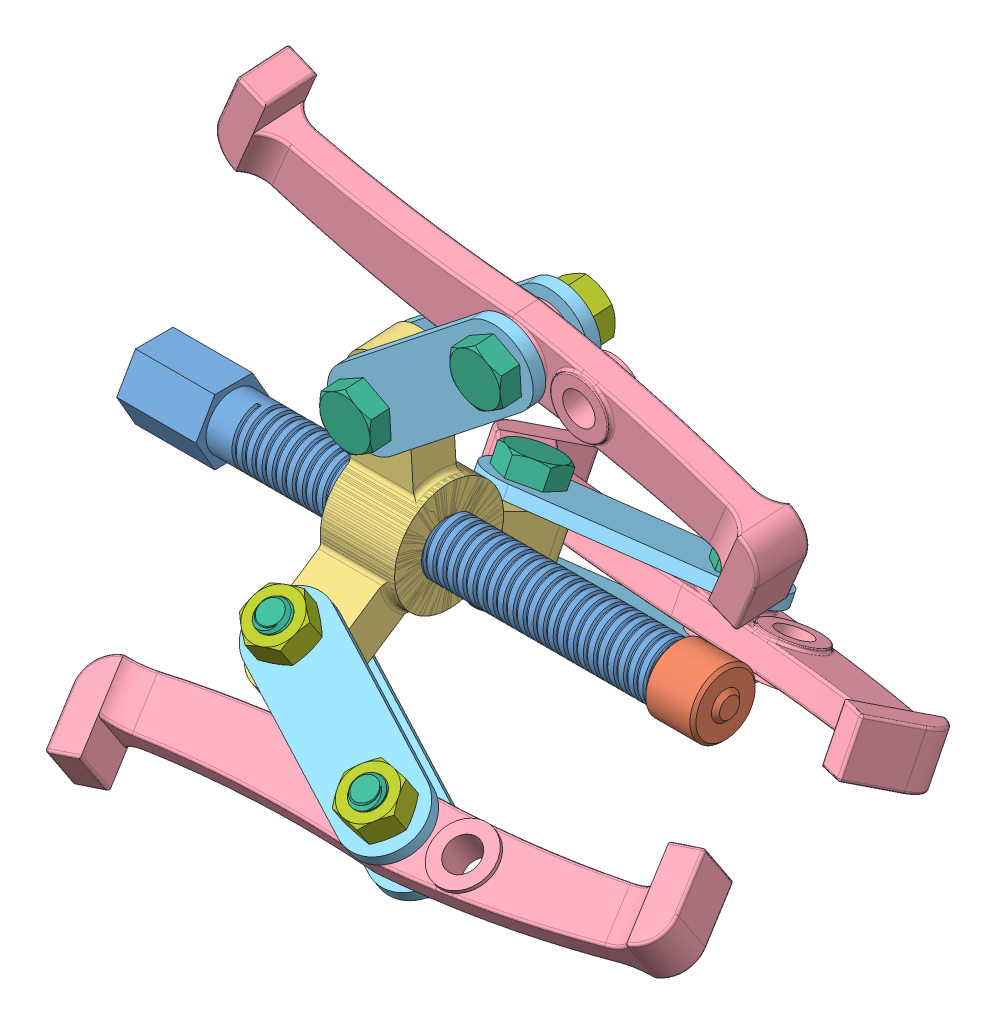
SolidWorks assembly DRAFT41-63 ASSEMBLY, configuration Default. Lengths in mm.
Overall size (173.92 155.65 156.59).
24 component instances, 7 part files, 48 mates.
Components (placement in the parent):
- DRAFT41-63 PUSH SCREW-1: DRAFT41-63 PUSH SCREW [Default] at origin size (144.02 16.5 19.05)
- DRAFT41-63E PUSH SCREW END-1: DRAFT41-63E PUSH SCREW END [Default] at (12.7 0 0) x (1 0 0) z (0 -0.815917 0.578169) size (13.72 16.51 16.51)
- DRAFT41-63 Y JOINT-1: DRAFT41-63 Y JOINT [Default] at (-76.0434 0 0) x (0 0.061257 -0.998122) z (0 -0.998122 -0.061257) size (76.61 18.8 66.34)
- DRAFT41-63A PULLER ARM-1: DRAFT41-63A PULLER ARM [Default] at (-37.0809 58.5168 3.5913) x (0.412849 0.909089 0.055793) z (0 -0.061257 0.998122) size (37.12 137.16 14.1)
- DRAFT41-63A LINKAGE-1: DRAFT41-63A LINKAGE [Default] at (-33.3881 57.3763 12.1354) x (0.779625 0.625071 0.038362) z (0 -0.061257 0.998122) size (63.5 19.05 3.17)
- DRAFT41-63A LINKAGE-2: DRAFT41-63A LINKAGE [Default] at (-33.3881 58.2351 -1.8591) x (0.779625 0.625071 0.038362) z (0 -0.061257 0.998122) size (63.5 19.05 3.17)
- 92240A583_18-8 Stainless Steel Hex Head Screw-1: 92240A583_18-8 Stainless Steel Hex Head Screw [92240A583] at (-68.0424 29.5918 10.4302) x (1 0 0) z (0 -0.061257 0.998122) size (12.7 14.66 31.1)
- 95505A602_Medium-Strength Steel Hex Nut-1: 95505A602_Medium-Strength Steel Hex Nut [95505A602] at (-68.0424 30.8519 -10.1004) x (0.994196 -0.107382 -0.00659) z (0 -0.061257 0.998122) size (12.7 14.66 7.85)
- 92240A583_18-8 Stainless Steel Hex Head Screw-2: 92240A583_18-8 Stainless Steel Hex Head Screw [92240A583] at (-33.3881 57.3763 12.1354) x (1 0 0) z (0 -0.061257 0.998122) size (12.7 14.66 31.1)
- 95505A602_Medium-Strength Steel Hex Nut-2: 95505A602_Medium-Strength Steel Hex Nut [95505A602] at (-33.3881 58.6363 -8.3952) x (1 0 0) z (0 0.061257 -0.998122) size (12.7 14.66 7.85)
- DRAFT41-63A LINKAGE-3: DRAFT41-63A LINKAGE [Default] at (-28.0194 -20.1681 46.0296) x (0.900406 -0.240197 0.362733) z (0 0.83377 0.552111) size (63.5 19.05 3.17)
- DRAFT41-63A LINKAGE-4: DRAFT41-63A LINKAGE [Default] at (-28.0194 -31.8583 38.2886) x (0.900406 -0.240197 0.362733) z (0 0.83377 0.552111) size (63.5 19.05 3.17)
- DRAFT41-63A PULLER ARM-2: DRAFT41-63A PULLER ARM [Default] at (-31.7616 -27.3954 41.3711) x (0.284892 -0.529232 0.799219) z (0 -0.83377 -0.552111) size (37.12 137.16 14.1)
- 92240A583_18-8 Stainless Steel Hex Head Screw-3: 92240A583_18-8 Stainless Steel Hex Head Screw [92240A583] at (-68.0424 -23.8287 20.4122) x (-0.503529 -0.477012 0.72036) z (0 -0.83377 -0.552111) size (12.7 14.66 31.1)
- 95505A602_Medium-Strength Steel Hex Nut-3: 95505A602_Medium-Strength Steel Hex Nut [95505A602] at (-68.0424 -6.6787 31.7687) x (-0.317356 0.523571 -0.79067) z (0 0.83377 0.552111) size (12.7 14.66 7.85)
- 92240A583_18-8 Stainless Steel Hex Head Screw-4: 92240A583_18-8 Stainless Steel Hex Head Screw [92240A583] at (-28.0194 -34.5055 36.5357) x (0.593838 -0.44422 0.670839) z (0 -0.83377 -0.552111) size (12.7 14.66 31.1)
- 95505A602_Medium-Strength Steel Hex Nut-4: 95505A602_Medium-Strength Steel Hex Nut [95505A602] at (-28.0194 -17.3555 47.8922) x (0.932993 0.198703 -0.30007) z (0 -0.83377 -0.552111) size (12.7 14.66 7.85)
- DRAFT41-63A PULLER ARM-3: DRAFT41-63A PULLER ARM [Default] at (-29.676 -20.0922 -40.3199) x (0.391979 -0.410318 -0.823402) z (0 0.895028 -0.446011) size (37.12 137.16 14.1)
- DRAFT41-63A LINKAGE-5: DRAFT41-63A LINKAGE [Default] at (-25.97 -27.5509 -36.0102) x (0.94651 -0.143917 -0.288804) z (0 -0.895028 0.446011) size (63.5 19.05 3.17)
- DRAFT41-63A LINKAGE-6: DRAFT41-63A LINKAGE [Default] at (-25.97 -15.0019 -42.2636) x (0.94651 -0.143917 -0.288804) z (0 -0.895028 0.446011) size (63.5 19.05 3.17)
- 92240A583_18-8 Stainless Steel Hex Head Screw-5: 92240A583_18-8 Stainless Steel Hex Head Screw [92240A583] at (-68.0424 -5.7631 -30.8424) x (0.553703 0.371399 0.745303) z (0 0.895028 -0.446011) size (12.7 14.66 31.1)
- 95505A602_Medium-Strength Steel Hex Nut-5: 95505A602_Medium-Strength Steel Hex Nut [95505A602] at (-68.0424 -24.1731 -21.6683) x (1 0 0) z (0 -0.895028 0.446011) size (12.7 14.66 7.85)
- 92240A583_18-8 Stainless Steel Hex Head Screw-6: 92240A583_18-8 Stainless Steel Hex Head Screw [92240A583] at (-25.97 -12.1602 -43.6797) x (0.63314 -0.345229 -0.692785) z (0 0.895028 -0.446011) size (12.7 14.66 31.1)
- 95505A602_Medium-Strength Steel Hex Nut-6: 95505A602_Medium-Strength Steel Hex Nut [95505A602] at (-25.97 -30.5702 -34.5056) x (0.991794 0.05702 0.114423) z (0 -0.895028 0.446011) size (12.7 14.66 7.85)
Mates (geometry in assembly coordinates):
- Concentric1: concentric anti-aligned: circle of DRAFT41-63 PUSH SCREW-1; circle of DRAFT41-63E PUSH SCREW END-1
- Coincident2: coincident anti-aligned: plane of DRAFT41-63 PUSH SCREW-1 through (10.16 0 0) normal (1 0 0); plane of DRAFT41-63E PUSH SCREW END-1 through (10.16 0 0) normal (-1 0 0)
- Concentric2: concentric aligned: circle of DRAFT41-63 PUSH SCREW-1; circle of DRAFT41-63 Y JOINT-1
- Concentric4: concentric anti-aligned: cylinder of DRAFT41-63 Y JOINT-1 through (-68.0424 27.7722 40.0792) axis (0 0.061257 -0.998122) radius 4.0323; cylinder of DRAFT41-63A LINKAGE-1 through (-68.0424 29.7863 7.2612) axis (0 -0.061257 0.998122) radius 4.7625
- Coincident3: coincident anti-aligned: plane of DRAFT41-63 Y JOINT-1 through (-60.0414 -14.0995 4.5678) normal (0 -0.061257 0.998122); plane of DRAFT41-63A LINKAGE-1 through (-33.3881 57.5707 8.9664) normal (0 0.061257 -0.998122)
- Concentric5: concentric anti-aligned: cylinder of DRAFT41-63 Y JOINT-1 through (-68.0424 27.7722 40.0792) axis (0 0.061257 -0.998122) radius 4.0323; cylinder of DRAFT41-63A LINKAGE-2 through (-68.0424 30.6452 -6.7333) axis (0 -0.061257 0.998122) radius 4.7625
- Coincident4: coincident anti-aligned: plane of DRAFT41-63 Y JOINT-1 through (-68.0424 33.3662 -3.3853) normal (0 0.061257 -0.998122); plane of DRAFT41-63A LINKAGE-2 through (-33.3881 58.2351 -1.8591) normal (0 -0.061257 0.998122)
- Concentric7: concentric aligned: cylinder of DRAFT41-63A LINKAGE-1 through (-33.3881 57.5707 8.9664) axis (0 -0.061257 0.998122) radius 4.7625; cylinder of DRAFT41-63A LINKAGE-2 through (-33.3881 58.4296 -5.0281) axis (0 -0.061257 0.998122) radius 4.7625
- Concentric8: concentric anti-aligned: cylinder of DRAFT41-63A PULLER ARM-1 through (-33.3881 57.6275 8.041) axis (0 0.061257 -0.998122) radius 4.1021; cylinder of DRAFT41-63A LINKAGE-1 through (-33.3881 57.5707 8.9664) axis (0 -0.061257 0.998122) radius 4.7625
- Width1: width anti-aligned: plane of DRAFT41-63A LINKAGE-2 through (-33.3881 58.2351 -1.8591) normal (0 -0.061257 0.998122); plane of DRAFT41-63A LINKAGE-1 through (-33.3881 57.5707 8.9664) normal (0 0.061257 -0.998122); plane of DRAFT41-63A PULLER ARM-1 through (-33.3881 58.1783 -0.9337) normal (0 0.061257 -0.998122); plane of DRAFT41-63A PULLER ARM-1 through (-33.3881 57.6275 8.041) normal (0 -0.061257 0.998122)
- Concentric9: concentric aligned: cylinder of DRAFT41-63 Y JOINT-1 through (-68.0424 27.7722 40.0792) axis (0 0.061257 -0.998122) radius 4.0323; circle of 92240A583_18-8 Stainless Steel Hex Head Screw-1
- Coincident5: coincident anti-aligned: plane of DRAFT41-63A LINKAGE-1 through (-33.3881 57.3763 12.1354) normal (0 -0.061257 0.998122); plane of 92240A583_18-8 Stainless Steel Hex Head Screw-1 through (-61.6924 33.2511 10.6548) normal (0 0.061257 -0.998122)
- Concentric10: concentric aligned: circle of DRAFT41-63A LINKAGE-2; circle of 95505A602_Medium-Strength Steel Hex Nut-1
- Coincident6: coincident anti-aligned: plane of DRAFT41-63A LINKAGE-2 through (-33.3881 58.4296 -5.0281) normal (0 0.061257 -0.998122); plane of 95505A602_Medium-Strength Steel Hex Nut-1 through (-73.9611 34.9651 -6.4682) normal (0 -0.061257 0.998122)
- Concentric11: concentric anti-aligned: circle of DRAFT41-63A LINKAGE-1; circle of 92240A583_18-8 Stainless Steel Hex Head Screw-2
- Coincident7: coincident anti-aligned: plane of DRAFT41-63A LINKAGE-1 through (-33.3881 57.3763 12.1354) normal (0 -0.061257 0.998122); plane of 92240A583_18-8 Stainless Steel Hex Head Screw-2 through (-27.0381 61.0355 12.36) normal (0 0.061257 -0.998122)
- Concentric12: concentric aligned: circle of 92240A583_18-8 Stainless Steel Hex Head Screw-2; circle of 95505A602_Medium-Strength Steel Hex Nut-2
- Coincident8: coincident anti-aligned: plane of DRAFT41-63A LINKAGE-2 through (-33.3881 58.4296 -5.0281) normal (0 0.061257 -0.998122); plane of 95505A602_Medium-Strength Steel Hex Nut-2 through (-39.7381 54.7703 -5.2527) normal (0 -0.061257 0.998122)
- Concentric13: concentric anti-aligned: cylinder of DRAFT41-63 Y JOINT-1 through (-68.0424 28.9826 55.3832) axis (0 -0.83377 -0.552111) radius 4.0323; cylinder of DRAFT41-63A LINKAGE-3 through (-68.0424 -12.1386 28.1532) axis (0 0.83377 0.552111) radius 4.7625
- Coincident9: coincident anti-aligned: plane of DRAFT41-63 Y JOINT-1 through (-68.0424 -13.7513 30.5887) normal (0 0.83377 0.552111); plane of DRAFT41-63A LINKAGE-3 through (-28.0194 -22.8154 44.2767) normal (0 -0.83377 -0.552111)
- Concentric14: concentric anti-aligned: cylinder of DRAFT41-63 Y JOINT-1 through (-68.0424 28.9826 55.3832) axis (0 -0.83377 -0.552111) radius 4.0323; cylinder of DRAFT41-63A LINKAGE-4 through (-68.0424 -23.8287 20.4122) axis (0 0.83377 0.552111) radius 4.7625
- Coincident10: coincident anti-aligned: plane of DRAFT41-63 Y JOINT-1 through (-60.0414 3.0939 -14.4944) normal (0 -0.83377 -0.552111); plane of DRAFT41-63A LINKAGE-4 through (-28.0194 -31.8583 38.2886) normal (0 0.83377 0.552111)
- Concentric15: concentric aligned: cylinder of DRAFT41-63A LINKAGE-3 through (-28.0194 -22.8154 44.2767) axis (0 0.83377 0.552111) radius 4.7625; cylinder of DRAFT41-63A LINKAGE-4 through (-28.0194 -34.5055 36.5357) axis (0 0.83377 0.552111) radius 4.7625
- Concentric16: concentric aligned: cylinder of DRAFT41-63A LINKAGE-3 through (-28.0194 -22.8154 44.2767) axis (0 0.83377 0.552111) radius 4.7625; cylinder of DRAFT41-63A PULLER ARM-2 through (-28.0194 -31.0853 38.8005) axis (0 0.83377 0.552111) radius 4.1021
- Width2: width aligned: plane of DRAFT41-63A LINKAGE-4 through (-28.0194 -31.8583 38.2886) normal (0 0.83377 0.552111); plane of DRAFT41-63A LINKAGE-3 through (-28.0194 -22.8154 44.2767) normal (0 -0.83377 -0.552111); plane of DRAFT41-63A PULLER ARM-2 through (-28.0194 -23.5883 43.7648) normal (0 0.83377 0.552111); plane of DRAFT41-63A PULLER ARM-2 through (-28.0194 -31.0853 38.8005) normal (0 -0.83377 -0.552111)
- Concentric17: concentric aligned: circle of DRAFT41-63A LINKAGE-3; circle of 95505A602_Medium-Strength Steel Hex Nut-3
- Coincident11: coincident anti-aligned: plane of DRAFT41-63A LINKAGE-3 through (-28.0194 -20.1681 46.0296) normal (0 0.83377 0.552111); plane of 95505A602_Medium-Strength Steel Hex Nut-3 through (-69.5038 -13.4584 35.897) normal (0 -0.83377 -0.552111)
- Concentric18: concentric anti-aligned: cylinder of DRAFT41-63 Y JOINT-1 through (-68.0424 28.9826 55.3832) axis (0 -0.83377 -0.552111) radius 4.0323; circle of 92240A583_18-8 Stainless Steel Hex Head Screw-3
- Coincident12: coincident anti-aligned: plane of DRAFT41-63A LINKAGE-4 through (-28.0194 -34.5055 36.5357) normal (0 -0.83377 -0.552111); plane of 92240A583_18-8 Stainless Steel Hex Head Screw-3 through (-74.4073 -25.8386 23.4473) normal (0 0.83377 0.552111)
- Concentric19: concentric aligned: cylinder of DRAFT41-63A PULLER ARM-2 through (-28.0194 -31.0853 38.8005) axis (0 0.83377 0.552111) radius 4.1021; circle of 92240A583_18-8 Stainless Steel Hex Head Screw-4
- Coincident13: coincident anti-aligned: plane of DRAFT41-63A LINKAGE-4 through (-28.0194 -34.5055 36.5357) normal (0 -0.83377 -0.552111); plane of 92240A583_18-8 Stainless Steel Hex Head Screw-4 through (-27.1982 -38.5283 42.6107) normal (0 0.83377 0.552111)
- Concentric20: concentric anti-aligned: circle of 92240A583_18-8 Stainless Steel Hex Head Screw-4; circle of 95505A602_Medium-Strength Steel Hex Nut-4
- Coincident14: coincident anti-aligned: plane of DRAFT41-63A LINKAGE-3 through (-28.0194 -20.1681 46.0296) normal (0 0.83377 0.552111); plane of 95505A602_Medium-Strength Steel Hex Nut-4 through (-32.6244 -23.3184 50.787) normal (0 -0.83377 -0.552111)
- Concentric21: concentric aligned: cylinder of DRAFT41-63 Y JOINT-1 through (-68.0424 35.5376 -51.4234) axis (0 -0.895028 0.446011) radius 4.0323; cylinder of DRAFT41-63A LINKAGE-5 through (-68.0424 -18.3121 -24.589) axis (0 -0.895028 0.446011) radius 4.7625
- Coincident15: coincident anti-aligned: plane of DRAFT41-63 Y JOINT-1 through (-68.0424 -19.6149 -27.2033) normal (0 -0.895028 0.446011); plane of DRAFT41-63A LINKAGE-5 through (-25.97 -24.7092 -37.4263) normal (0 0.895028 -0.446011)
- Concentric22: concentric aligned: cylinder of DRAFT41-63 Y JOINT-1 through (-68.0424 35.5376 -51.4234) axis (0 -0.895028 0.446011) radius 4.0323; cylinder of DRAFT41-63A LINKAGE-6 through (-68.0424 -5.7631 -30.8424) axis (0 -0.895028 0.446011) radius 4.7625
- Coincident16: coincident anti-aligned: plane of DRAFT41-63 Y JOINT-1 through (-60.0414 11.0056 9.9266) normal (0 0.895028 -0.446011); plane of DRAFT41-63A LINKAGE-6 through (-25.97 -15.0019 -42.2636) normal (0 -0.895028 0.446011)
- Concentric23: concentric aligned: cylinder of DRAFT41-63A LINKAGE-5 through (-25.97 -24.7092 -37.4263) axis (0 -0.895028 0.446011) radius 4.7625; cylinder of DRAFT41-63A LINKAGE-6 through (-25.97 -12.1602 -43.6797) axis (0 -0.895028 0.446011) radius 4.7625
- Concentric24: concentric aligned: cylinder of DRAFT41-63A PULLER ARM-3 through (-25.97 -15.8317 -41.8501) axis (0 -0.895028 0.446011) radius 4.1021; cylinder of DRAFT41-63A LINKAGE-6 through (-25.97 -12.1602 -43.6797) axis (0 -0.895028 0.446011) radius 4.7625
- Width3: width aligned: plane of DRAFT41-63A LINKAGE-5 through (-25.97 -24.7092 -37.4263) normal (0 0.895028 -0.446011); plane of DRAFT41-63A LINKAGE-6 through (-25.97 -15.0019 -42.2636) normal (0 -0.895028 0.446011); plane of DRAFT41-63A PULLER ARM-3 through (-25.97 -15.8317 -41.8501) normal (0 0.895028 -0.446011); plane of DRAFT41-63A PULLER ARM-3 through (-25.97 -23.8794 -37.8398) normal (0 -0.895028 0.446011)
- Concentric25: concentric aligned: circle of DRAFT41-63A LINKAGE-6; circle of 92240A583_18-8 Stainless Steel Hex Head Screw-5
- Coincident17: coincident anti-aligned: plane of DRAFT41-63A LINKAGE-6 through (-25.97 -12.1602 -43.6797) normal (0 0.895028 -0.446011); plane of 92240A583_18-8 Stainless Steel Hex Head Screw-5 through (-61.4735 -4.3101 -27.9266) normal (0 -0.895028 0.446011)
- Concentric26: concentric aligned: circle of 92240A583_18-8 Stainless Steel Hex Head Screw-5; circle of 95505A602_Medium-Strength Steel Hex Nut-5
- Coincident18: coincident anti-aligned: plane of DRAFT41-63A LINKAGE-5 through (-25.97 -27.5509 -36.0102) normal (0 -0.895028 0.446011); plane of 95505A602_Medium-Strength Steel Hex Nut-5 through (-74.3924 -19.5187 -19.8916) normal (0 0.895028 -0.446011)
- Concentric27: concentric aligned: cylinder of DRAFT41-63A PULLER ARM-3 through (-25.97 -15.8317 -41.8501) axis (0 -0.895028 0.446011) radius 4.1021; circle of 92240A583_18-8 Stainless Steel Hex Head Screw-6
- Coincident19: coincident anti-aligned: plane of DRAFT41-63A LINKAGE-6 through (-25.97 -12.1602 -43.6797) normal (0 0.895028 -0.446011); plane of 92240A583_18-8 Stainless Steel Hex Head Screw-6 through (-24.7874 -15.3877 -50.1564) normal (0 -0.895028 0.446011)
- Concentric28: concentric aligned: circle of DRAFT41-63A LINKAGE-5; circle of 95505A602_Medium-Strength Steel Hex Nut-6
- Coincident20: coincident anti-aligned: plane of DRAFT41-63A LINKAGE-5 through (-25.97 -27.5509 -36.0102) normal (0 -0.895028 0.446011); plane of 95505A602_Medium-Strength Steel Hex Nut-6 through (-32.7366 -26.2913 -33.4824) normal (0 0.895028 -0.446011)
